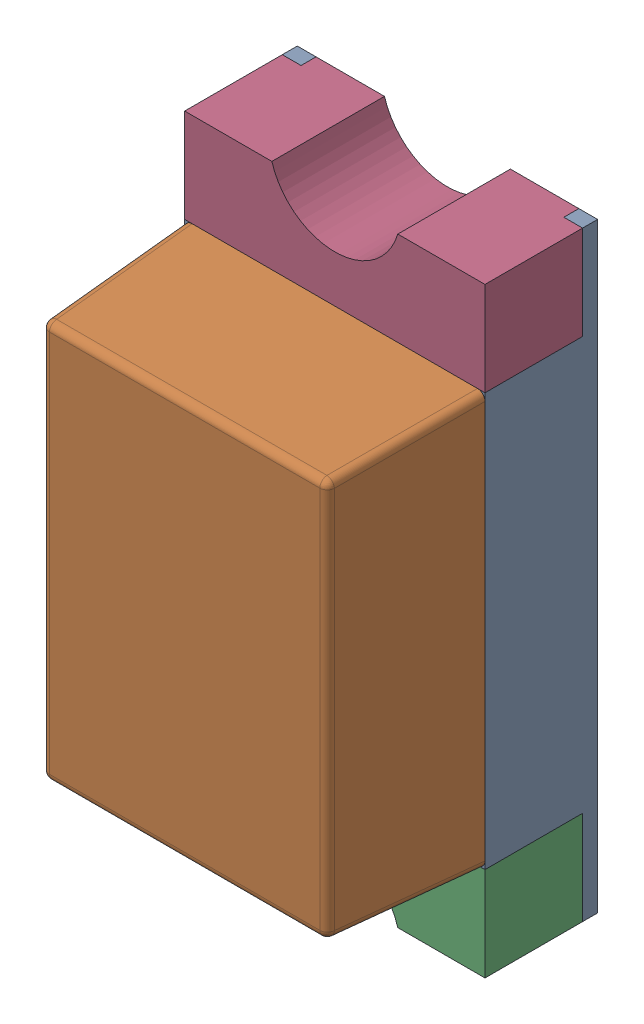
SolidWorks assembly LED202PCB, configuration Default. Lengths in mm.
Overall size (0.8 1.6 0.7).
6 component instances, 4 part files, 0 mates.
Components (placement in the parent):
- WL-SMCW_0603_LED-1: WL-SMCW_0603_LED [Default] at (93.2999 128.4001 0) x (0 1 0) z (0 0 1) size (1.6 0.8 0.7)
  - housing-1: housing [Default] at origin size (1.6 0.8 0.3)
  - cover-1: cover [Default] at (0 0 0.3) size (1.1 0.8 0.4)
  - base-1: base [Default] at (-0.675 0 0) size (0.45 0.8 0.3)
  - base-2: base [Default] at (0.675 0 0) x (-1 0 0) z (0 0 1) size (0.45 0.8 0.3)
  - Polarity_Mark-1: Polarity_Mark [Default] at (-0.675 0.35 0.3) size (0.25 0.1 0)
